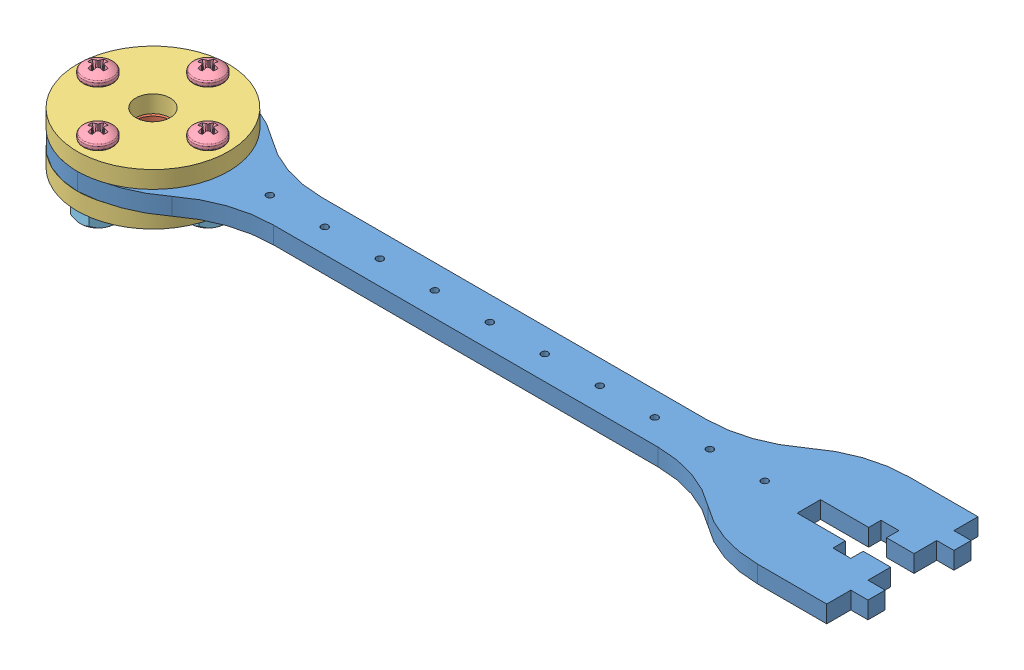
SolidWorks assembly boom_assembly, configuration Default. Lengths in mm.
Overall size (156.63 14.77 30.54).
12 component instances, 5 part files, 24 mates.
Components (placement in the parent):
- boom-1: boom [Default] at (5.8183 -4.6868 0.1139) size (155.58 3.17 27.94)
- bearing_57155K356-1: bearing_57155K356 [57155K356] at (-56.4117 -3.0993 0.1139) x (1 0 0) z (0 1 0) size (12.7 12.7 3.17)
- boom_bearing_cap_hex-1: boom_bearing_cap_hex [Default] at (-56.4117 1.6632 0.1139) x (-1 0 0) z (0 0 1) size (27.94 3.17 27.94)
- boom_bearing_cap_hex-3: boom_bearing_cap_hex [Default] at (-56.4117 -4.6868 0.1139) x (-1 0 0) z (0 0 1) size (27.94 3.17 27.94)
- 440_1-2_90272A110-1: 440_1-2_90272A110 [90272A110] at (-46.2517 -11.0368 0.1139) x (1 0 0) z (0 1 0) size (5.56 5.56 14.77)
- 440_1-2_90272A110-2: 440_1-2_90272A110 [90272A110] at (-56.4117 -11.0368 10.2739) x (1 0 0) z (0 1 0) size (5.56 5.56 14.77)
- 440_1-2_90272A110-3: 440_1-2_90272A110 [90272A110] at (-66.5717 -11.0368 0.1139) x (1 0 0) z (0 1 0) size (5.56 5.56 14.77)
- 440_1-2_90272A110-4: 440_1-2_90272A110 [90272A110] at (-56.4117 -11.0368 -10.0461) x (1 0 0) z (0 1 0) size (5.56 5.56 14.77)
- 440_nut_90480A005-9: 440_nut_90480A005 [90480A005] at (-66.5717 -7.8618 0.1139) x (-0.837169 0 -0.546944) z (-0.546944 0 0.837169) size (6.35 2.38 8.06)
- 440_nut_90480A005-10: 440_nut_90480A005 [90480A005] at (-56.4117 -7.8618 -10.0461) x (-0.837169 0 -0.546944) z (-0.546944 0 0.837169) size (6.35 2.38 8.06)
- 440_nut_90480A005-11: 440_nut_90480A005 [90480A005] at (-46.2517 -7.8618 0.1139) x (-0.837169 0 -0.546944) z (-0.546944 0 0.837169) size (6.35 2.38 8.06)
- 440_nut_90480A005-12: 440_nut_90480A005 [90480A005] at (-56.4117 -7.8618 10.2739) x (-0.837169 0 -0.546944) z (-0.546944 0 0.837169) size (6.35 2.38 8.06)
Mates (geometry in assembly coordinates):
- Coincident1: coincident aligned: plane of boom-1 through (5.8183 -1.5118 0.1139) normal (0 1 0); plane of bearing_57155K356-1 through (-56.4117 -1.5118 -6.0774) normal (0 1 0)
- Concentric1: concentric aligned: circle of boom-1; circle of bearing_57155K356-1
- Coincident3: coincident anti-aligned: plane of boom-1 through (5.8183 -1.5118 0.1139) normal (0 1 0); plane of boom_bearing_cap_hex-1 through (-56.4117 -1.5118 0.1139) normal (0 -1 0)
- Concentric4: concentric anti-aligned: circle of boom-1; circle of boom_bearing_cap_hex-1
- Concentric6: concentric anti-aligned: circle of boom-1; circle of boom_bearing_cap_hex-1
- Coincident29: coincident anti-aligned: plane of boom-1 through (5.8183 -4.6868 0.1139) normal (0 -1 0); plane of boom_bearing_cap_hex-3 through (-56.4117 -4.6868 0.1139) normal (0 1 0)
- Concentric18: concentric anti-aligned: circle of boom-1; circle of boom_bearing_cap_hex-3
- Concentric19: concentric anti-aligned: circle of boom-1; circle of boom_bearing_cap_hex-3
- Coincident33: coincident anti-aligned: plane of boom_bearing_cap_hex-1 through (-56.4117 1.6632 0.1139) normal (0 1 0); plane of 440_1-2_90272A110-1 through (-46.2517 1.6632 0.1139) normal (0 -1 0)
- Coincident34: coincident anti-aligned: plane of boom_bearing_cap_hex-1 through (-56.4117 1.6632 0.1139) normal (0 1 0); plane of 440_1-2_90272A110-2 through (-56.4117 1.6632 10.2739) normal (0 -1 0)
- Coincident35: coincident anti-aligned: plane of boom_bearing_cap_hex-1 through (-56.4117 1.6632 0.1139) normal (0 1 0); plane of 440_1-2_90272A110-3 through (-66.5717 1.6632 0.1139) normal (0 -1 0)
- Coincident36: coincident anti-aligned: plane of boom_bearing_cap_hex-1 through (-56.4117 1.6632 0.1139) normal (0 1 0); plane of 440_1-2_90272A110-4 through (-56.4117 1.6632 -10.0461) normal (0 -1 0)
- Concentric20: concentric anti-aligned: circle of boom_bearing_cap_hex-1; circle of 440_1-2_90272A110-4
- Concentric21: concentric anti-aligned: circle of boom_bearing_cap_hex-1; circle of 440_1-2_90272A110-3
- Concentric22: concentric anti-aligned: circle of boom_bearing_cap_hex-1; circle of 440_1-2_90272A110-2
- Concentric23: concentric anti-aligned: circle of boom_bearing_cap_hex-1; circle of 440_1-2_90272A110-1
- Coincident37: coincident anti-aligned: plane of boom_bearing_cap_hex-3 through (-56.4117 -7.8618 0.1139) normal (0 -1 0); plane of 440_nut_90480A005-12 through (-54.4065 -7.8618 7.2047) normal (0 1 0)
- Coincident38: coincident anti-aligned: plane of boom_bearing_cap_hex-3 through (-56.4117 -7.8618 0.1139) normal (0 -1 0); plane of 440_nut_90480A005-11 through (-44.2465 -7.8618 -2.9553) normal (0 1 0)
- Coincident39: coincident anti-aligned: plane of boom_bearing_cap_hex-3 through (-56.4117 -7.8618 0.1139) normal (0 -1 0); plane of 440_nut_90480A005-10 through (-54.4065 -7.8618 -13.1153) normal (0 1 0)
- Coincident40: coincident anti-aligned: plane of boom_bearing_cap_hex-3 through (-56.4117 -7.8618 0.1139) normal (0 -1 0); plane of 440_nut_90480A005-9 through (-64.5665 -7.8618 -2.9553) normal (0 1 0)
- Concentric24: concentric anti-aligned: circle of boom_bearing_cap_hex-3; circle of 440_nut_90480A005-9
- Concentric25: concentric anti-aligned: circle of boom_bearing_cap_hex-3; circle of 440_nut_90480A005-10
- Concentric26: concentric anti-aligned: circle of boom_bearing_cap_hex-3; circle of 440_nut_90480A005-11
- Concentric27: concentric anti-aligned: circle of boom_bearing_cap_hex-3; circle of 440_nut_90480A005-12
